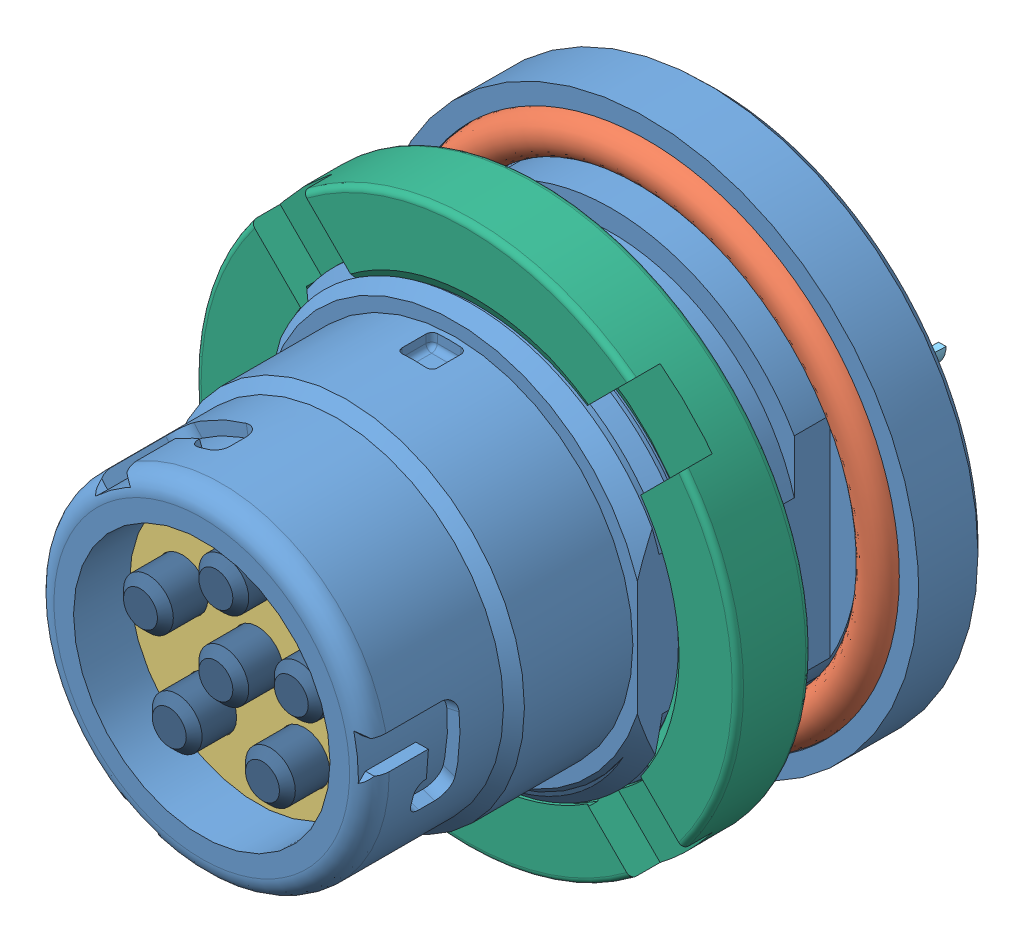
SolidWorks assembly M55116_10-0 v7, configuration Default. Lengths in mm.
Overall size (34.41 34.41 29.28).
42 component instances, 10 part files, 0 mates.
Components (placement in the parent):
- Housing Metal-1: Housing Metal [Default] at (73.025 80.137 -6.223) size (24.34 24.34 23.04)
- O-Ring - Outer-1: O-Ring - Outer [Default] at (73.025 80.137 -6.223) size (22.61 22.61 1.78)
- Plastic Housing - Upper-1: Plastic Housing - Upper [Default] at (73.025 80.137 -6.223) size (13.16 13.16 16.89)
- Plastic Housing - Lower-1: Plastic Housing - Lower [Default] at (73.025 80.137 -6.223) size (13.16 13.16 3.81)
- Solder Cup-1: Solder Cup [Default] at (73.025 80.137 -6.223) size (2.79 2.79 11.66)
- Retaining Nut-1: Retaining Nut [Default] at (73.025 80.137 -5.7404) x (-0.707107 0.707107 0) z (0 0 1) size (24.33 24.33 3.32)
- O-Ring - Inner-1: O-Ring - Inner [Default] at (73.025 80.137 -6.223) size (13.46 13.46 2.54)
- Pogo Spring Asmbly-1: Pogo Spring Asmbly [Default] at origin size (2.95 2.95 19.03)
  - Pogo Spring-1: Pogo Spring [Default] at (73.025 80.137 -6.223) size (2.88 2.88 16.26)
  - Pogo Pin Asmbly-1: Pogo Pin Asmbly [Default] at origin size (2.95 2.95 7.62)
    - Pogo O-Ring-1: Pogo O-Ring [Default] at (73.025 80.137 -6.223) size (2.92 2.92 0.76)
    - Pogo Contact Pin-1: Pogo Contact Pin [Default] at (73.025 80.137 -6.223) size (2.95 2.95 7.62)
- Solder Cup-2: Solder Cup [Default] at (73.025 83.693 -6.223) size (2.79 2.79 11.66)
- Pogo Spring Asmbly_2-1: Pogo Spring Asmbly_2 [Default] at (0 12.7 0) size (2.95 2.95 19.03)
  - Pogo Spring-1: Pogo Spring [Default] at (73.025 70.993 -6.223) size (2.88 2.88 16.26)
  - Pogo Pin Asmbly_2-1: Pogo Pin Asmbly_2 [Default] at origin size (2.95 2.95 7.62)
    - Pogo O-Ring-1: Pogo O-Ring [Default] at (73.025 70.993 -6.223) size (2.92 2.92 0.76)
    - Pogo Contact Pin-1: Pogo Contact Pin [Default] at (73.025 70.993 -6.223) size (2.95 2.95 7.62)
- Pogo Spring Asmbly_3-1: Pogo Spring Asmbly_3 [Default] at (0 19.05 0) size (2.95 2.95 19.03)
  - Pogo Spring-1: Pogo Spring [Default] at (69.643 62.1859 -6.223) size (2.88 2.88 16.26)
  - Pogo Pin Asmbly_3-1: Pogo Pin Asmbly_3 [Default] at origin size (2.95 2.95 7.62)
    - Pogo O-Ring-1: Pogo O-Ring [Default] at (69.643 62.1859 -6.223) size (2.92 2.92 0.76)
    - Pogo Contact Pin-1: Pogo Contact Pin [Default] at (69.643 62.1859 -6.223) size (2.95 2.95 7.62)
- Solder Cup-3: Solder Cup [Default] at (69.643 81.2359 -6.223) size (2.79 2.79 11.66)
- Pogo Spring Asmbly_4-1: Pogo Spring Asmbly_4 [Default] at (0 25.4 0) size (2.95 2.95 19.03)
  - Pogo Spring-1: Pogo Spring [Default] at (70.9348 51.8601 -6.223) size (2.88 2.88 16.26)
  - Pogo Pin Asmbly_4-1: Pogo Pin Asmbly_4 [Default] at origin size (2.95 2.95 7.62)
    - Pogo O-Ring-1: Pogo O-Ring [Default] at (70.9348 51.8601 -6.223) size (2.92 2.92 0.76)
    - Pogo Contact Pin-1: Pogo Contact Pin [Default] at (70.9348 51.8601 -6.223) size (2.95 2.95 7.62)
- Solder Cup-4: Solder Cup [Default] at (70.9348 77.2601 -6.223) size (2.79 2.79 11.66)
- Pogo Spring Asmbly_5-1: Pogo Spring Asmbly_5 [Default] at (0 31.75 0) size (2.95 2.95 19.03)
  - Pogo Spring-1: Pogo Spring [Default] at (75.1152 45.5101 -6.223) size (2.88 2.88 16.26)
  - Pogo Pin Asmbly_5-1: Pogo Pin Asmbly_5 [Default] at origin size (2.95 2.95 7.62)
    - Pogo O-Ring-1: Pogo O-Ring [Default] at (75.1152 45.5101 -6.223) size (2.92 2.92 0.76)
    - Pogo Contact Pin-1: Pogo Contact Pin [Default] at (75.1152 45.5101 -6.223) size (2.95 2.95 7.62)
- Solder Cup-5: Solder Cup [Default] at (75.1152 77.2601 -6.223) size (2.79 2.79 11.66)
- Pogo Spring Asmbly_6-1: Pogo Spring Asmbly_6 [Default] at (0 38.1 0) size (2.95 2.95 19.03)
  - Pogo Spring-1: Pogo Spring [Default] at (76.407 43.1359 -6.223) size (2.88 2.88 16.26)
  - Pogo Pin Asmbly_6-1: Pogo Pin Asmbly_6 [Default] at origin size (2.95 2.95 7.62)
    - Pogo O-Ring-1: Pogo O-Ring [Default] at (76.407 43.1359 -6.223) size (2.92 2.92 0.76)
    - Pogo Contact Pin-1: Pogo Contact Pin [Default] at (76.407 43.1359 -6.223) size (2.95 2.95 7.62)
- Solder Cup-6: Solder Cup [Default] at (76.407 81.2359 -6.223) size (2.79 2.79 11.66)
